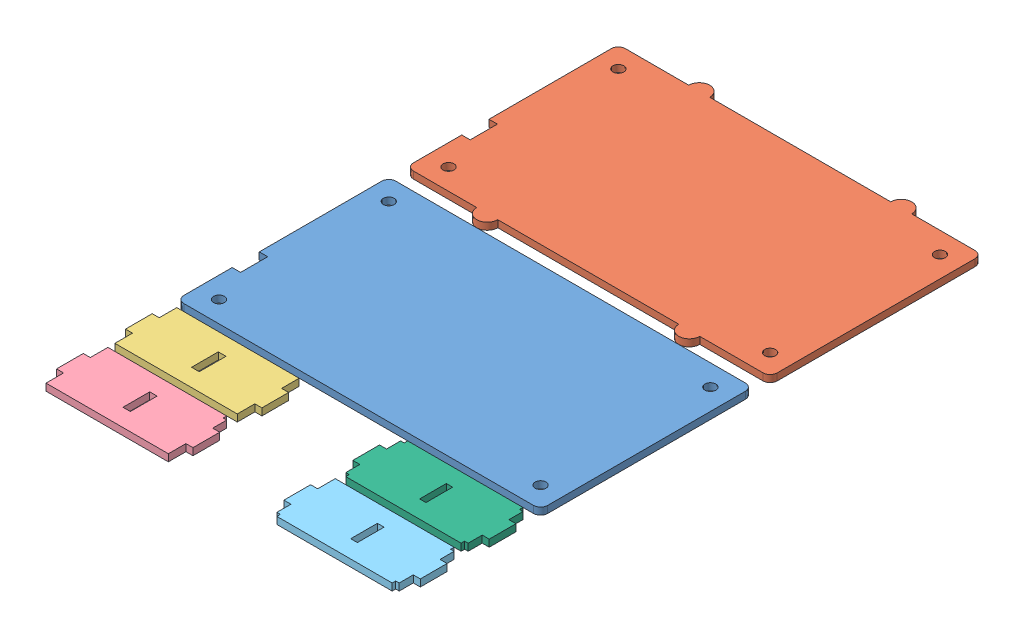
SolidWorks assembly compose_for_cut, configuration 默认. Lengths in mm.
Overall size (103.46 2 167.78).
6 component instances, 6 part files, 15 mates.
Components (placement in the parent):
- back-1: back [默认] at (-64.4621 13.5294 24.145) size (103.46 2 60.29)
- front-1: front [默认] at (-64.4621 13.5294 -41.145) size (103.46 2 66.29)
- side-1: side [默认] at (-68.4621 13.5294 32.145) x (0 0 1) z (-1 0 0) size (17.6 2 38.8)
- side_2-1: side_2 [默认] at (-68.4621 13.5294 51.745) x (0 0 1) z (-1 0 0) size (17.6 2 38.8)
- side_4-1: side_4 [默认] at (-3.8021 13.5294 51.745) x (0 0 1) z (-1 0 0) size (17.6 2 38.8)
- side_5-1: side_5 [默认] at (-3.8021 13.5294 32.145) x (0 0 1) z (-1 0 0) size (17.6 2 38.8)
Mates (geometry in assembly coordinates):
- 重合1: coincident aligned: plane of back-1 through (-64.4621 13.5294 24.145) normal (0 -1 0); plane of front-1 through (-64.4621 13.5294 -41.145) normal (0 -1 0)
- 重合3: coincident: plane of back-1 through (-64.4621 13.5294 24.145) normal (0 -1 0); plane of side_5-1 through (-3.8021 13.5294 35.3081) normal (0 -1 0)
- 重合4: coincident: plane of back-1 through (-64.4621 13.5294 24.145) normal (0 -1 0); plane of side_4-1 through (-3.8021 13.5294 55.6153) normal (0 -1 0)
- 重合5: coincident aligned: plane of back-1 through (-64.4621 13.5294 24.145) normal (0 -1 0); plane of side_2-1 through (-68.4621 13.5294 51.745) normal (0 -1 0)
- 重合6: coincident aligned: plane of back-1 through (-64.4621 13.5294 24.145) normal (0 -1 0); plane of side-1 through (-68.4621 13.5294 32.145) normal (0 -1 0)
- 重合7: coincident aligned: plane of back-1 through (-70.4621 15.5294 24.145) normal (-1 0 0); plane of side-1 through (-70.4621 15.5294 32.145) normal (-1 0 0)
- 重合8: coincident aligned: plane of back-1 through (-70.4621 15.5294 24.145) normal (-1 0 0); plane of side_2-1 through (-70.4621 15.5294 51.745) normal (-1 0 0)
- 重合9: coincident: plane of back-1 through (32.9979 15.5294 24.145) normal (1 0 0); plane of side_5-1 through (32.9979 15.5294 35.3081) normal (1 0 0)
- 重合10: coincident: plane of back-1 through (32.9979 15.5294 24.145) normal (1 0 0); plane of side_4-1 through (32.9979 15.5294 55.6153) normal (1 0 0)
- 重合11: coincident aligned: plane of back-1 through (32.9979 15.5294 24.145) normal (1 0 0); plane of front-1 through (32.9979 15.5294 -41.145) normal (1 0 0)
- 距离1: distance = 5 mm anti-aligned: plane of back-1 through (-64.4621 15.5294 -30.145) normal (0 0 -1); plane of front-1 through (-64.4621 15.5294 -35.145) normal (0 0 1)
- 距离2: distance = 2 mm anti-aligned: plane of side-1 through (-68.4621 15.5294 32.145) normal (0 0 -1); plane of back-1 through (-64.4621 15.5294 30.145) normal (0 0 1)
- 距离3: distance = 2 mm anti-aligned: plane of side-1 through (-68.4621 15.5294 49.745) normal (0 0 1); plane of side_2-1 through (-68.4621 15.5294 51.745) normal (0 0 -1)
- 距离4: distance = 2 mm anti-aligned: plane of back-1 through (-64.4621 15.5294 30.145) normal (0 0 1); plane of side_5-1 through (-3.8021 15.5294 32.145) normal (0 0 -1)
- 距离5: distance = 2 mm anti-aligned: plane of side_5-1 through (-3.8021 15.5294 49.745) normal (0 0 1); plane of side_4-1 through (-3.8021 15.5294 51.745) normal (0 0 -1)
